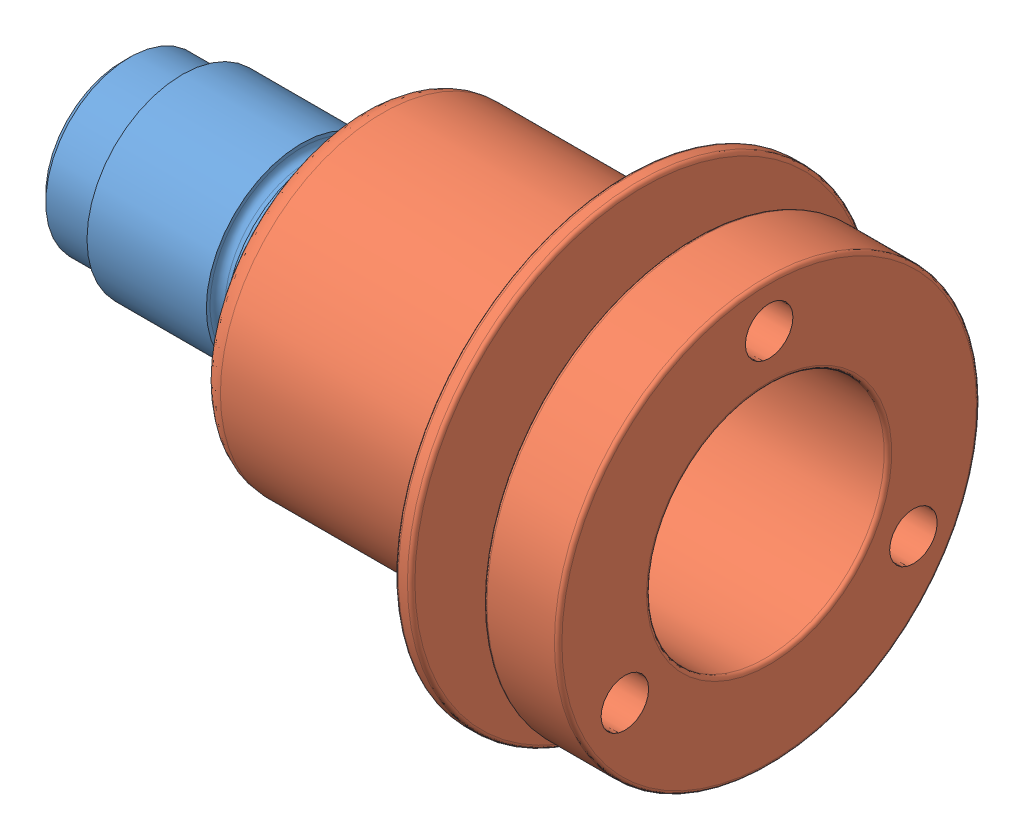
SolidWorks assembly WheelHubDisconnect, configuration Default. Lengths in mm.
Overall size (86.3 64.09 61.9).
2 component instances, 2 part files, 5 mates.
Components (placement in the parent):
- SteeringWheelDisconnectSpline-1: SteeringWheelDisconnectSpline [Default] at origin size (55 25.4 25.4)
- SteeringWheelDisconnect-1: SteeringWheelDisconnect [Default] at (31.3 0 0) x (0 0 -1) z (1 0 0) size (61.9 64.09 54.6)
Mates (geometry in assembly coordinates):
- Coincident1: coincident: plane of assembly through (0 0 0) normal (0 0 1); plane of SteeringWheelDisconnectSpline-1 through (0 0 0) normal (0 0 1); plane of assembly
- Coincident2: coincident: plane of assembly through (0 0 0) normal (0 1 0); plane of SteeringWheelDisconnectSpline-1 through (0 0 0) normal (0 1 0); plane of assembly
- Coincident3: coincident: plane of assembly through (0 0 0) normal (1 0 0); plane of SteeringWheelDisconnectSpline-1 through (0 0 0) normal (1 0 0); plane of assembly
- Concentric1: concentric: cylinder of assembly; cylinder of assembly; cylinder of SteeringWheelDisconnectSpline-1 through (19.1683 0 0) axis (1 0 0) radius 12.7; cylinder of SteeringWheelDisconnect-1 through (41.1624 0 0) axis (1 0 0) radius 15.85
- Distance1: distance = 86.3 mm: plane of assembly; plane of assembly; plane of SteeringWheelDisconnect-1 through (31.3 15.85 0) normal (1 0 0); plane of SteeringWheelDisconnectSpline-1 through (-55 10.2 0) normal (-1 0 0)
